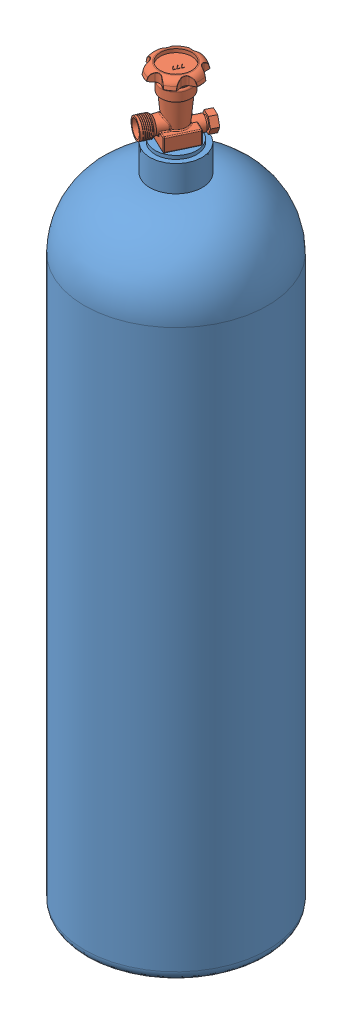
SolidWorks assembly OxTank_Assy, configuration Default. Lengths in mm.
Overall size (133.35 535.03 133.35).
2 component instances, 2 part files, 3 mates.
Components (placement in the parent):
- M24_OxTank-1: M24_OxTank [Default] at origin size (133.35 486.41 133.35)
- M24_Valve-1: M24_Valve [Default] at (0 481.33 0) x (-0.429874 0 0.902889) z (-0.902889 0 -0.429874) size (43.69 53.7 33.5)
Mates (geometry in assembly coordinates):
- Concentric1: concentric anti-aligned: cylinder of M24_OxTank-1 through (0 486.41 0) axis (0 -1 0) radius 9.525; circle of M24_Valve-1
- Coincident1: coincident anti-aligned: plane of M24_OxTank-1 through (0 486.41 0) normal (0 1 0); plane of M24_Valve-1 through (0 486.41 0) normal (0 -1 0)
- Parallel1: parallel anti-aligned: plane of M24_OxTank-1 through (0 486.41 0) normal (0 1 0); plane of M24_Valve-1 through (0 481.33 0) normal (0 -1 0)
